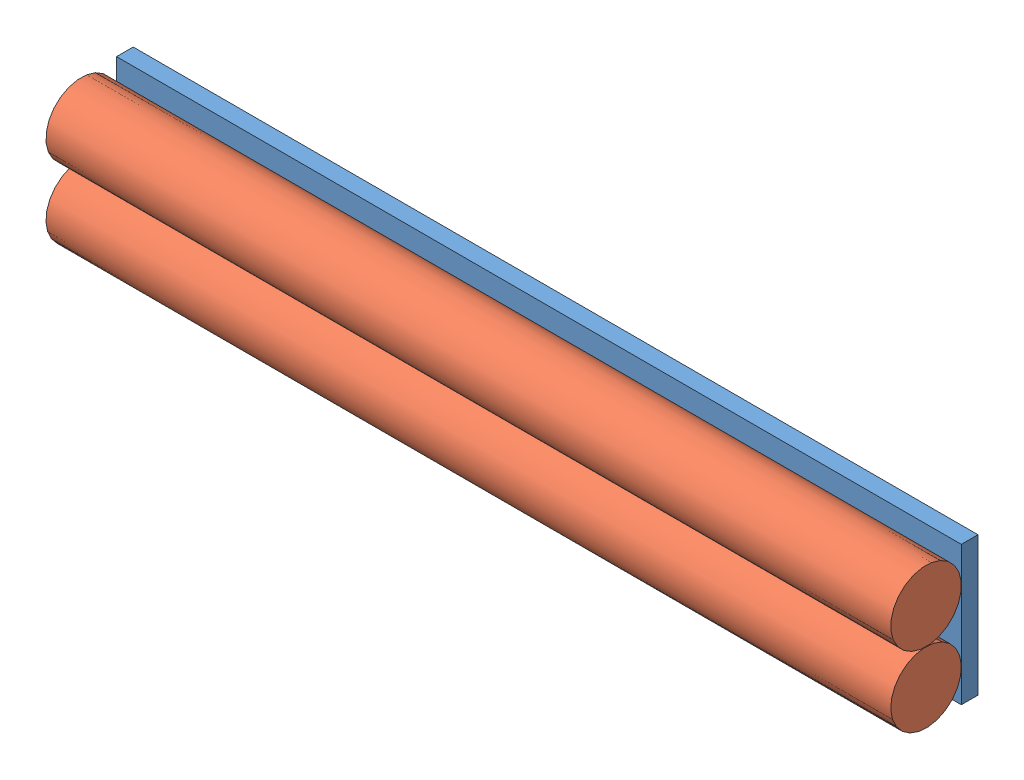
SolidWorks assembly Bumper, configuration Default. Lengths in mm.
Overall size (760 148.52 90.64).
3 component instances, 2 part files, 5 mates.
Components (placement in the parent):
- Wood-1: Wood [Default] at (216.3082 417.3321 604.8417) size (760 125 15)
- Foam-1: Foam [Default] at (-163.6918 447.7174 651.5917) x (0 -0.363902 0.931437) z (1 0 0) size (63.5 63.5 760)
- Foam-3: Foam [Default] at (-163.6918 384.2174 651.5917) x (0 0.840256 0.542191) z (1 0 0) size (63.5 63.5 760)
Mates (geometry in assembly coordinates):
- Coincident1: coincident: line of Wood-1 through (596.3082 354.8321 619.8417) axis (0 1 0); plane of Foam-1 through (596.3082 447.7174 651.5917) normal (1 0 0)
- Tangent1: tangent anti-aligned: plane of Wood-1 through (216.3082 417.3321 619.8417) normal (0 0 1); cylinder of Foam-1 through (596.3082 447.7174 651.5917) axis (-1 0 0) radius 31.75
- Tangent2: tangent anti-aligned: plane of Wood-1 through (216.3082 417.3321 619.8417) normal (0 0 1); cylinder of Foam-3 through (596.3082 384.2174 651.5917) axis (-1 0 0) radius 31.75
- Coincident3: coincident: line of Wood-1 through (-163.6918 479.8321 619.8417) axis (0 -1 0); plane of Foam-3 through (-163.6918 384.2174 651.5917) normal (-1 0 0)
- Tangent3: tangent: cylinder of Foam-1 through (596.3082 447.7174 651.5917) axis (-1 0 0) radius 31.75; cylinder of Foam-3 through (596.3082 384.2174 651.5917) axis (-1 0 0) radius 31.75
